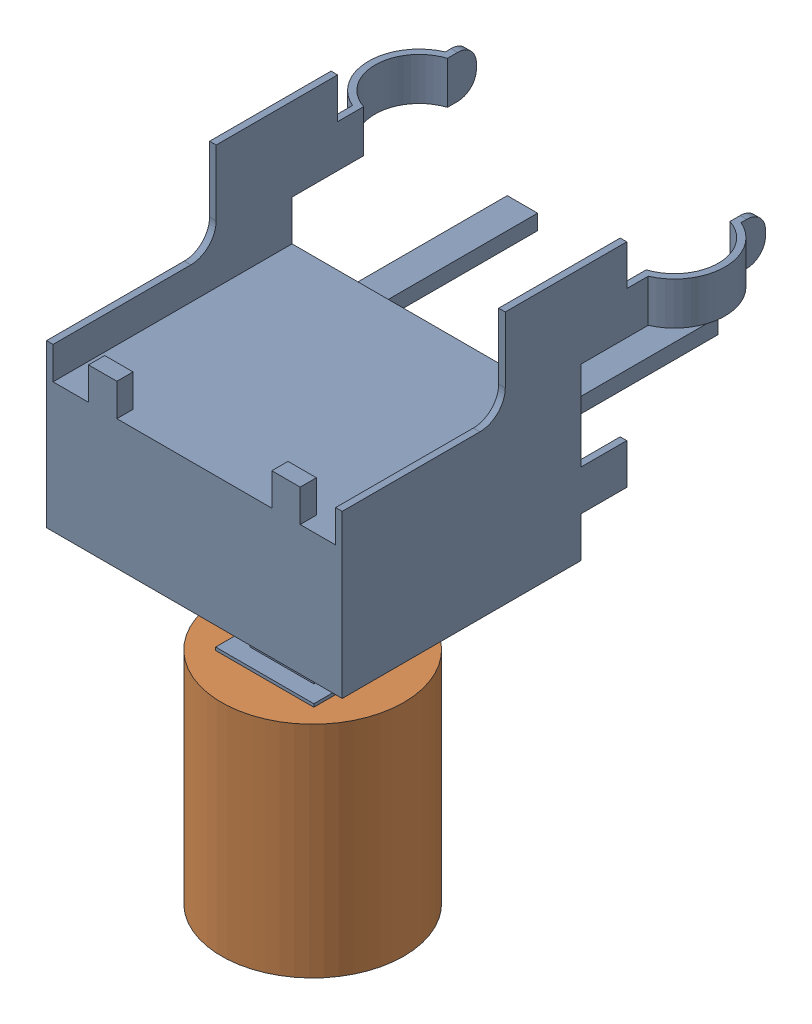
SolidWorks assembly SW2, configuration Default. Lengths in mm.
Overall size (8.94 14.17 10.62).
3 component instances, 2 part files, 0 mates.
Components (placement in the parent):
- User_Library-omron_b3f-3152-1: User_Library-omron_b3f-3152 [Default] at (8.4782 -0.0509 4.191) x (1 0 0) z (0 -1 0) size (8.94 10.62 10.36)
- 75857376-1: 75857376 [Default] at (8.4491 -2.3623 4.191) x (1 0 0) z (0 -1 0) size (4.57 4.57 5.51)
  - Cylinder-1: Cylinder [Default] at origin size (4.57 4.57 5.51)
